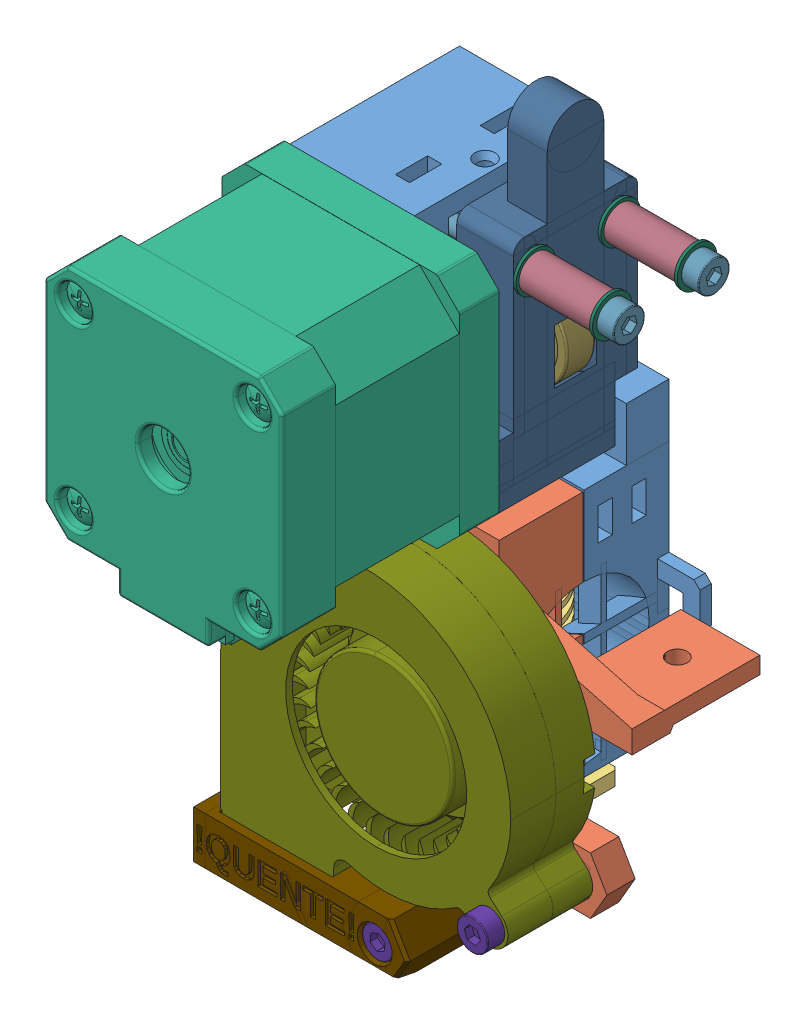
SolidWorks assembly Assembly Extruder, configuration Valor predeterminado. Lengths in mm.
Overall size (71.84 121.62 68.91).
43 component instances, 21 part files, 97 mates.
Components (placement in the parent):
- extruder-body-2: extruder-body [Valor predeterminado] at (45 44 0) x (-1 0 0) z (0 0 1) size (52.5 86 30)
- Nut DIN 934 - M3-1: Nut DIN 934 - M3 [Valor predeterminado] at (15.5 37.5 12.2) x (0 0 1) z (0.866025 0.5 0) size (2.4 5.5 6.35)
- Nut DIN 934 - M3-2: Nut DIN 934 - M3 [Valor predeterminado] at (4.5 39.5 4.79) x (0 0 1) z (-0.258819 0.965926 0) size (2.4 5.5 6.35)
- Nut DIN 934 - M3-3: Nut DIN 934 - M3 [Valor predeterminado] at (39.5 37.5 11.3) x (0 0 1) z (0.5 0.866025 0) size (2.4 5.5 6.35)
- Nut DIN 934 - M3-4: Nut DIN 934 - M3 [Valor predeterminado] at (39.5 37.5 5.2) x (0 0 1) z (1 0 0) size (2.4 5.5 6.35)
- Nut DIN 934 - M3-5: Nut DIN 934 - M3 [Valor predeterminado] at (23.3 80.7 22.5) x (1 0 0) z (0 -0.5 -0.866025) size (2.4 5.5 6.35)
- Nut DIN 934 - M3-6: Nut DIN 934 - M3 [Valor predeterminado] at (23.3 80.7 7.5) x (1 0 0) z (0 -0.5 -0.866025) size (2.4 5.5 6.35)
- Hotend E3D V6-1: Hotend E3D V6 [Valor predeterminado] at (-22.5 1.0005 15) x (0 0 -1) z (0 1 0) size (26.65 22.3 62.82)
- Nut DIN 934 - M3-7: Nut DIN 934 - M3 [Valor predeterminado] at (58.25 -1 26.81) x (0 0 -1) z (1 0 0) size (2.4 5.5 6.35)
- Nut DIN 934 - M3-8: Nut DIN 934 - M3 [Valor predeterminado] at (15.5 37.5 26.81) x (0 0 1) z (-0.866025 -0.5 0) size (2.4 5.5 6.35)
- Screw DIN 912 - M3 x 16 --- 16N-1: Screw DIN 912 - M3 x 16 --- 16N [Valor predeterminado] at (39.5 37.5 29) x (0 0 1) z (-0.911999 0.410192 0) size (19 5.5 5.5)
- Screw DIN 912 - M3 x 25 --- 18N-1: Screw DIN 912 - M3 x 25 --- 18N [Valor predeterminado] at (4.5 39.5 30) x (0 0 1) z (-0.994804 0.10181 0) size (28 5.5 5.5)
- Stepper motor Nema 17-1: Stepper motor Nema 17 [Valor predeterminado] at (-0.1278 69.2544 42.5) x (0 0 1) z (0 -1 0) size (62.01 42.01 48.01)
- PTFE tube-1: PTFE tube [Valor predeterminado] at (27.5 60.9828 15) x (0.286766 0 -0.958001) z (0 -1 0) size (4.2 4.2 49.4)
- Filament drive gear MK8 - 9 x 11-1: Filament drive gear MK8 - 9 x 11 [Valor predeterminado] at (24 65 22.65) x (0.970505 -0.241083 0) z (0.241083 0.970505 0) size (9 11 9.5)
- Screw DIN 912 - M3 x 30 --- 18N-1: Screw DIN 912 - M3 x 30 --- 18N [Valor predeterminado] at (8.5 49.5 0.5) x (0 0 -1) z (0.942704 0.333631 0) size (33 5.5 5.5)
- Screw DIN 912 - M3 x 30 --- 18N-2: Screw DIN 912 - M3 x 30 --- 18N [Valor predeterminado] at (39.5 49.5 0.5) x (0 0 -1) z (-0.421121 0.907005 0) size (33 5.5 5.5)
- extruder-idler-1: extruder-idler [Valor predeterminado] at (43.5 45.5 15) x (0 0 1) z (-1 0 0) size (25.5 57 10)
- idler-shaft-1: idler-shaft [Valor predeterminado] at (36.5 65.5 23) x (-0.827991 -0.560742 0) z (0 0 -1) size (5 5 16)
- Radial ball bearing DIN 625 - 625-1: Radial ball bearing DIN 625 - 625 [Valor predeterminado] at (36.5 65.5 15) x (0 0 1) z (-1 0 0) size (5 16 16)
- Extruder spring-1: Extruder spring [Valor predeterminado] at (44 80.7 22.5) x (0 0 -1) z (1 0 0) size (6 6 13)
- Screw DIN 912 - M3 x 40 --- 18N-1: Screw DIN 912 - M3 x 40 --- 18N [Valor predeterminado] at (60.5 80.7 22.5) x (1 0 0) z (0 0.973566 0.228405) size (43 5.5 5.5)
- Washer DIN 125A - M3-1: Washer DIN 125A - M3 [Valor predeterminado] at (57 80.7 22.5) size (0.5 7 7)
- Washer DIN 125A - M3-2: Washer DIN 125A - M3 [Valor predeterminado] at (43.5 80.7 22.5) size (0.5 7 7)
- Extruder spring-2: Extruder spring [Valor predeterminado] at (44 80.7 7.5) x (0 -0.311049 -0.950394) z (1 0 0) size (6 6 13)
- Washer DIN 125A - M3-3: Washer DIN 125A - M3 [Valor predeterminado] at (43.5 80.7 7.5) size (0.5 7 7)
- Washer DIN 125A - M3-4: Washer DIN 125A - M3 [Valor predeterminado] at (57 80.7 7.5) size (0.5 7 7)
- Screw DIN 912 - M3 x 40 --- 18N-2: Screw DIN 912 - M3 x 40 --- 18N [Valor predeterminado] at (60.5 80.7 7.5) x (1 0 0) z (0 0.973566 0.228405) size (43 5.5 5.5)
- Radial flow fan - 50 x 15-1: Radial flow fan - 50 x 15 [Valor predeterminado] at (38.25 17 30) x (1 0 0) z (0 -1 0) size (51.3 15 51.07)
- Screw DIN 912 - M3 x 20 --- 20N-1: Screw DIN 912 - M3 x 20 --- 20N [Valor predeterminado] at (58.25 -1 48) x (0 0 1) z (0.388777 -0.921332 0) size (23 5.5 5.5)
- Screw DIN 912 - M3 x 20 --- 20N-2: Screw DIN 912 - M3 x 20 --- 20N [Valor predeterminado] at (15.5 37.5 48) x (0 0 1) z (-0.788848 -0.614588 0) size (23 5.5 5.5)
- Screw DIN 912 - M3 x 20 --- 20N-3: Screw DIN 912 - M3 x 20 --- 20N [Valor predeterminado] at (40 -12 46.5) x (0 0 1) z (-0.111158 -0.993803 0) size (23 5.5 5.5)
- fan-nozzle-1: fan-nozzle [Valor predeterminado] at (10 -17 30) size (38.8 10.05 23)
- Axil flow fan - 30 x 30 x 10-1: Axil flow fan - 30 x 30 x 10 [Valor predeterminado] at (-0.34 16 15) x (0 0 -1) z (1 0 0) size (30 30 10.44)
- Screw DIN 912 - M3 x 16 --- 16N-2: Screw DIN 912 - M3 x 16 --- 16N [Valor predeterminado] at (-3.34 28 3) x (-1 0 0) z (0 -0.998394 0.056645) size (19 5.5 5.5)
- Screw DIN 912 - M3 x 16 --- 16N-3: Screw DIN 912 - M3 x 16 --- 16N [Valor predeterminado] at (-3.34 28 27) x (-1 0 0) z (0 0.857394 -0.514661) size (19 5.5 5.5)
- Screw DIN 912 - M3 x 16 --- 16N-4: Screw DIN 912 - M3 x 16 --- 16N [Valor predeterminado] at (-3.34 4 3) x (-1 0 0) z (0 -0.998394 0.056645) size (19 5.5 5.5)
- Screw DIN 912 - M3 x 16 --- 16N-5: Screw DIN 912 - M3 x 16 --- 16N [Valor predeterminado] at (-3.34 4 27) x (-1 0 0) z (0 -0.998394 0.056645) size (19 5.5 5.5)
- Washer DIN 125A - M3-5: Washer DIN 125A - M3 [Valor predeterminado] at (39.5 49.5 8) x (0 0 -1) z (0.997029 0.077029 0) size (0.5 7 7)
- Washer DIN 125A - M3-6: Washer DIN 125A - M3 [Valor predeterminado] at (39.5 49.5 30) x (0 0 -1) z (-0.467035 0.884239 0) size (0.5 7 7)
- extruder-cover-1: extruder-cover [Valor predeterminado] at (45 44 0) x (-1 0 0) z (0 0 1) size (68.5 60.8 22.6)
- Washer DIN 125A - M5-1: Washer DIN 125A - M5 [Valor predeterminado] at (36.5 65.5 12.25) x (0 0 -1) z (0.971355 -0.237634 0) size (1 10 10)
- Washer DIN 125A - M5-2: Washer DIN 125A - M5 [Valor predeterminado] at (36.5 65.5 18.75) x (0 0 -1) z (0.971355 -0.237634 0) size (1 10 10)
Mates (geometry in assembly coordinates):
- Coincidente1: coincident: plane of ? through (45 44 0) normal (0 0 -1); plane of assembly through (0 0 0) normal (0 0 1)
- Coincidente2: coincident: plane of ? through (0 44 0) normal (-1 0 0); plane of assembly through (0 0 0) normal (1 0 0)
- Coincidente3: coincident: plane of ? through (45 0 0) normal (0 -1 0); plane of assembly through (0 0 0) normal (0 1 0)
- Concêntrico1: concentric: cylinder of ? through (15.5 37.5 -0.01) axis (0 0 1) radius 1.65; cylinder of Nut DIN 934 - M3-1 through (15.5 37.5 13.4) axis (0 0 -1) radius 1.25
- Paralelo1: parallel: plane of ? through (18.2713 39.1 11) normal (-0.5 -0.866025 0); plane of Nut DIN 934 - M3-1 through (12.75 35.9123 13.4) normal (-0.5 -0.866025 0)
- Coincidente5: coincident: plane of ? through (15.5 37.5 11) normal (0 0 1); plane of Nut DIN 934 - M3-1 through (12.75 39.0877 11) normal (0 0 -1)
- Concêntrico2: concentric: cylinder of ? through (4.5 39.5 6.2) axis (0 0 1) radius 1.7; cylinder of Nut DIN 934 - M3-2 through (4.5 39.5 5.99) axis (0 0 -1) radius 1.25
- Paralelo2: parallel: plane of ? through (6.7627 41.7627 -0.01) normal (-0.258819 -0.965926 0); plane of Nut DIN 934 - M3-2 through (2.2546 37.2546 5.99) normal (-0.258819 -0.965926 0)
- Coincidente7: coincident: plane of ? through (4.5 39.5 5.99) normal (0 0 -1); plane of Nut DIN 934 - M3-2 through (2.2546 37.2546 5.99) normal (0 0 1)
- Concêntrico3: concentric: cylinder of ? through (39.5 37.5 12.7) axis (0 0 1) radius 1.65; cylinder of Nut DIN 934 - M3-3 through (39.5 37.5 12.5) axis (0 0 -1) radius 1.25
- Paralelo3: parallel: plane of ? through (46 34.65 10) normal (0 1 0); plane of Nut DIN 934 - M3-3 through (41.0877 40.25 12.5) normal (0 1 0)
- Coincidente9: coincident: plane of ? through (46 40.35 12.5) normal (0 0 -1); plane of Nut DIN 934 - M3-3 through (36.3246 37.5 12.5) normal (0 0 1)
- Concêntrico4: concentric: cylinder of ? through (39.5 37.5 -0.01) axis (0 0 1) radius 1.65; cylinder of Nut DIN 934 - M3-4 through (39.5 37.5 6.4) axis (0 0 -1) radius 1.25
- Paralelo4: parallel: plane of ? through (46 34.65 4) normal (0 1 0); plane of Nut DIN 934 - M3-4 through (37.9123 34.75 6.4) normal (0 -1 0)
- Coincidente11: coincident: plane of ? through (46 40.35 4) normal (0 0 1); plane of Nut DIN 934 - M3-4 through (37.9123 40.25 4) normal (0 0 -1)
- Coincidente12: coincident: line of ? through (30.275 80.7 22.5) axis (-1 0 0); line of Nut DIN 934 - M3-5 through (24.5 80.7 22.5) axis (-1 0 0)
- Paralelo5: parallel: plane of ? through (22 97.5 19.65) normal (0 0 1); plane of Nut DIN 934 - M3-5 through (24.5 82.2877 25.25) normal (0 0 1)
- Coincidente14: coincident: plane of ? through (24.5 97.5 19.65) normal (-1 0 0); plane of Nut DIN 934 - M3-5 through (24.5 83.8754 22.5) normal (1 0 0)
- Coincidente15: coincident: line of ? through (30.275 80.7 7.5) axis (-1 0 0); line of Nut DIN 934 - M3-6 through (24.5 80.7 7.5) axis (-1 0 0)
- Paralelo6: parallel: plane of ? through (22 97.5 4.65) normal (0 0 1); plane of Nut DIN 934 - M3-6 through (24.5 82.2877 10.25) normal (0 0 1)
- Coincidente17: coincident: plane of ? through (24.5 97.5 4.65) normal (-1 0 0); plane of Nut DIN 934 - M3-6 through (24.5 83.8754 7.5) normal (1 0 0)
- Concêntrico5: concentric: cylinder of ? through (27.5 44 15) axis (0 -1 0) radius 7.13; cylinder of Hotend E3D V6-1 through (27.5 37.0005 15) axis (0 -1 0) radius 6
- Paralelo7: parallel: plane of ? through (45 44 0) normal (1 0 0); plane of Hotend E3D V6-1 through (35.5 -8.3673 9.5) normal (1 0 0)
- Coincidente20: coincident: plane of ? through (45 37.0005 0) normal (0 -1 0); plane of Hotend E3D V6-1 through (-22.5 37.0005 15) normal (0 -1 0)
- Coincidente28: coincident: plane of ? through (3 86 30) normal (0 0 1); plane of Stepper motor Nema 17-1 through (24 65 30) normal (0 0 -1)
- Concêntrico13: concentric: cylinder of ? through (8.5 80.5 4) axis (0 0 1) radius 1.65; cylinder of Stepper motor Nema 17-1 through (8.5 80.5 33.5) axis (0 0 -1) radius 1.5
- Concêntrico14: concentric: cylinder of ? through (8.5 49.5 4) axis (0 0 1) radius 1.65; cylinder of Stepper motor Nema 17-1 through (8.5 49.5 33.5) axis (0 0 -1) radius 1.5
- Concêntrico15: concentric: cylinder of assembly; cylinder of assembly; cylinder of Hotend E3D V6-1 through (27.5 13.7005 15) axis (0 -1 0) radius 2.1; cylinder of PTFE tube-1 through (27.5 11.5827 15) axis (0 1 0) radius 2.1
- Coincidente29: coincident: plane of assembly; plane of assembly; plane of Hotend E3D V6-1 through (27.5 11.5827 15) normal (0 1 0); plane of PTFE tube-1 through (27.5 11.5827 15) normal (0 -1 0)
- Concêntrico16: concentric: cylinder of assembly; cylinder of assembly; cylinder of Stepper motor Nema 17-1 through (24 65 34.4) axis (0 0 1) radius 2.5; cylinder of Filament drive gear MK8 - 9 x 11-1 through (24 65 12.15) axis (0 0 -1) radius 2.5
- Coincidente30: coincident: line of assembly; plane of assembly; line of PTFE tube-1 through (27.5 11.5827 15) axis (0 1 0); plane of Filament drive gear MK8 - 9 x 11-1 through (24 65 15) normal (0 0 -1)
- Concêntrico17: concentric: cylinder of ? through (8.5 49.5 -1) axis (0 0 1) radius 3.1; cylinder of Screw DIN 912 - M3 x 30 --- 18N-1 through (8.5 49.5 0.5) axis (0 0 -1) radius 1.5
- Concêntrico18: concentric: cylinder of ? through (39.5 49.5 -1) axis (0 0 1) radius 3.1; cylinder of Screw DIN 912 - M3 x 30 --- 18N-2 through (39.5 49.5 0.5) axis (0 0 -1) radius 1.5
- Coincidente31: coincident: plane of ? through (39.5 49.5 3.5) normal (0 0 -1); plane of Screw DIN 912 - M3 x 30 --- 18N-2 through (37.0057 48.3419 3.5) normal (0 0 1)
- Coincidente32: coincident: plane of ? through (8.5 49.5 3.5) normal (0 0 -1); plane of Screw DIN 912 - M3 x 30 --- 18N-1 through (7.5825 52.0924 3.5) normal (0 0 1)
- Concêntrico19: concentric: cylinder of assembly; cylinder of assembly; cylinder of extruder-idler-1 through (36.5 65.5 6.5) axis (0 0 1) radius 2.5; cylinder of idler-shaft-1 through (36.5 65.5 22) axis (0 0 -1) radius 2.5
- Coincidente33: coincident: plane of assembly; plane of assembly; plane of extruder-idler-1 through (43.5 45.5 15) normal (0 0 -1); plane of idler-shaft-1 through (36.5 65.5 15) normal (0 0 -1)
- Concêntrico20: concentric: cylinder of assembly; cylinder of assembly; cylinder of Screw DIN 912 - M3 x 30 --- 18N-2 through (39.5 49.5 0.5) axis (0 0 -1) radius 1.5; cylinder of extruder-idler-1 through (39.5 49.5 0) axis (0 0 1) radius 1.7
- Coincidente34: coincident: plane of assembly through (0 0 18.75) normal (0 0 1); plane of extruder-idler-1 through (43.5 45.5 18.75) normal (0 0 1); plane of assembly
- Concêntrico21: concentric: cylinder of assembly; cylinder of assembly; cylinder of idler-shaft-1 through (36.5 65.5 22) axis (0 0 -1) radius 2.5; cylinder of Radial ball bearing DIN 625 - 625-1 through (36.5 65.5 -5.6375) axis (0 0 1) radius 2.5
- Coincidente35: coincident: plane of assembly; plane of assembly; plane of idler-shaft-1 through (36.5 65.5 15) normal (0 0 -1); plane of Radial ball bearing DIN 625 - 625-1 through (36.5 65.5 15) normal (0 0 1)
- Concêntrico22: concentric: cylinder of assembly; cylinder of assembly; cylinder of Screw DIN 912 - M3 x 40 --- 18N-1 through (60.5 80.7 22.5) axis (1 0 0) radius 1.5; cylinder of Washer DIN 125A - M3-1 through (57.5 80.7 22.5) axis (-1 0 0) radius 1.6
- Concêntrico23: concentric: cylinder of assembly; cylinder of assembly; cylinder of Screw DIN 912 - M3 x 40 --- 18N-1 through (60.5 80.7 22.5) axis (1 0 0) radius 1.5; cylinder of Washer DIN 125A - M3-2 through (44 80.7 22.5) axis (-1 0 0) radius 1.6
- Coincidente37: coincident: plane of assembly; plane of assembly; plane of Screw DIN 912 - M3 x 40 --- 18N-1 through (57.5 81.3281 19.8227) normal (-1 0 0); plane of Washer DIN 125A - M3-1 through (57.5 80.7 22.5) normal (1 0 0)
- Concêntrico24: concentric: cylinder of assembly; cylinder of assembly; cylinder of Extruder spring-1 through (57 80.7 22.5) axis (-1 0 0) radius 2.1; cylinder of Screw DIN 912 - M3 x 40 --- 18N-1 through (60.5 80.7 22.5) axis (1 0 0) radius 1.5
- Coincidente38: coincident: plane of assembly; plane of assembly; plane of Extruder spring-1 through (57 80.7 22.5) normal (1 0 0); plane of Washer DIN 125A - M3-1 through (57 80.7 22.5) normal (-1 0 0)
- Coincidente39: coincident: plane of assembly; plane of assembly; plane of Extruder spring-1 through (44 80.7 22.5) normal (-1 0 0); plane of Washer DIN 125A - M3-2 through (44 80.7 22.5) normal (1 0 0)
- Concêntrico25: concentric: cylinder of assembly; cylinder of assembly; cylinder of Nut DIN 934 - M3-5 through (24.5 80.7 22.5) axis (-1 0 0) radius 1.25; cylinder of Screw DIN 912 - M3 x 40 --- 18N-1 through (60.5 80.7 22.5) axis (1 0 0) radius 1.5
- Coincidente40: coincident: plane of assembly; plane of assembly; plane of extruder-idler-1 through (43.5 56.5 4) normal (1 0 0); plane of Washer DIN 125A - M3-2 through (43.5 80.7 22.5) normal (-1 0 0)
- Concêntrico26: concentric: cylinder of assembly; cylinder of assembly; cylinder of Washer DIN 125A - M3-4 through (57.5 80.7 7.5) axis (-1 0 0) radius 1.6; cylinder of Screw DIN 912 - M3 x 40 --- 18N-2 through (60.5 80.7 7.5) axis (1 0 0) radius 1.5
- Concêntrico27: concentric: cylinder of assembly; cylinder of assembly; cylinder of Washer DIN 125A - M3-3 through (44 80.7 7.5) axis (-1 0 0) radius 1.6; cylinder of Screw DIN 912 - M3 x 40 --- 18N-2 through (60.5 80.7 7.5) axis (1 0 0) radius 1.5
- Concêntrico28: concentric: cylinder of assembly; cylinder of assembly; cylinder of Extruder spring-2 through (57 80.7 7.5) axis (-1 0 0) radius 2.1; cylinder of Screw DIN 912 - M3 x 40 --- 18N-2 through (60.5 80.7 7.5) axis (1 0 0) radius 1.5
- Coincidente41: coincident: plane of assembly; plane of assembly; plane of Extruder spring-2 through (57 80.7 7.5) normal (1 0 0); plane of Washer DIN 125A - M3-4 through (57 80.7 7.5) normal (-1 0 0)
- Coincidente42: coincident: plane of assembly; plane of assembly; plane of Extruder spring-2 through (44 80.7 7.5) normal (-1 0 0); plane of Washer DIN 125A - M3-3 through (44 80.7 7.5) normal (1 0 0)
- Coincidente43: coincident: plane of assembly; plane of assembly; plane of Washer DIN 125A - M3-4 through (57.5 80.7 7.5) normal (1 0 0); plane of Screw DIN 912 - M3 x 40 --- 18N-2 through (57.5 81.3281 4.8227) normal (-1 0 0)
- Concêntrico29: concentric: cylinder of assembly; cylinder of assembly; cylinder of Nut DIN 934 - M3-6 through (24.5 80.7 7.5) axis (-1 0 0) radius 1.25; cylinder of Screw DIN 912 - M3 x 40 --- 18N-2 through (60.5 80.7 7.5) axis (1 0 0) radius 1.5
- Coincidente44: coincident: plane of assembly; plane of assembly; plane of extruder-idler-1 through (43.5 49.5 10) normal (1 0 0); plane of Washer DIN 125A - M3-3 through (43.5 80.7 7.5) normal (-1 0 0)
- Coincidente47: coincident: plane of assembly; plane of assembly; plane of Radial flow fan - 50 x 15-1 through (15.25 37 45) normal (0 0 1); plane of Screw DIN 912 - M3 x 20 --- 20N-1 through (55.7163 -2.0691 45) normal (0 0 -1)
- Coincidente48: coincident: plane of assembly; plane of assembly; plane of Radial flow fan - 50 x 15-1 through (15.25 37 45) normal (0 0 1); plane of Screw DIN 912 - M3 x 20 --- 20N-2 through (13.8099 39.6693 45) normal (0 0 -1)
- Coincidente50: coincident: plane of assembly; plane of assembly; plane of Screw DIN 912 - M3 x 20 --- 20N-3 through (37.267 -11.6943 43.5) normal (0 0 -1); plane of fan-nozzle-1 through (40 -12 43.5) normal (0 0 1)
- Concêntrico36: concentric: cylinder of ? through (9.999 28 3) axis (1 0 0) radius 1.35; cylinder of Axil flow fan - 30 x 30 x 10-1 through (-0.34 28 3) axis (1 0 0) radius 1.7
- Coincidente53: coincident: plane of ? through (45 44 0) normal (0 0 -1); plane of Axil flow fan - 30 x 30 x 10-1 through (-0.34 1 0) normal (0 0 -1)
- Coincidente54: coincident: plane of ? through (10 44 0) normal (-1 0 0); plane of Axil flow fan - 30 x 30 x 10-1 through (10 16 15) normal (1 0 0)
- Concêntrico38: concentric: cylinder of ? through (9.999 28 3) axis (1 0 0) radius 1.35; cylinder of Screw DIN 912 - M3 x 16 --- 16N-2 through (-3.34 28 3) axis (-1 0 0) radius 1.5
- Concêntrico39: concentric: cylinder of ? through (9.999 4 3) axis (1 0 0) radius 1.5; cylinder of Screw DIN 912 - M3 x 16 --- 16N-4 through (-3.34 4 3) axis (-1 0 0) radius 1.5
- Coincidente55: coincident: plane of assembly; plane of assembly; plane of Axil flow fan - 30 x 30 x 10-1 through (-0.34 16 15) normal (-1 0 0); plane of Screw DIN 912 - M3 x 16 --- 16N-4 through (-0.34 3.8442 0.2544) normal (1 0 0)
- Coincidente56: coincident: plane of assembly; plane of assembly; plane of Axil flow fan - 30 x 30 x 10-1 through (-0.34 16 15) normal (-1 0 0); plane of Screw DIN 912 - M3 x 16 --- 16N-3 through (-0.34 29.4153 29.3578) normal (1 0 0)
- Coincidente57: coincident: plane of assembly; plane of assembly; plane of Axil flow fan - 30 x 30 x 10-1 through (-0.34 16 15) normal (-1 0 0); plane of Screw DIN 912 - M3 x 16 --- 16N-2 through (-0.34 27.8442 0.2544) normal (1 0 0)
- Coincidente58: coincident: plane of assembly; plane of assembly; plane of Axil flow fan - 30 x 30 x 10-1 through (-0.34 16 15) normal (-1 0 0); plane of Screw DIN 912 - M3 x 16 --- 16N-5 through (-0.34 3.8442 24.2544) normal (1 0 0)
- Coincidente60: coincident: plane of assembly; plane of assembly; plane of extruder-idler-1 through (33.5 49.5 8) normal (0 0 -1); plane of Washer DIN 125A - M3-5 through (39.5 49.5 8) normal (0 0 1)
- Concêntrico41: concentric: cylinder of assembly; cylinder of assembly; cylinder of Screw DIN 912 - M3 x 30 --- 18N-2 through (39.5 49.5 0.5) axis (0 0 -1) radius 1.5; cylinder of Washer DIN 125A - M3-5 through (39.5 49.5 7.5) axis (0 0 1) radius 1.6
- Coincidente61: coincident: plane of assembly; plane of assembly; plane of extruder-idler-1 through (37.5 45.5 29.5) normal (0 0 1); plane of Washer DIN 125A - M3-6 through (39.5 49.5 29.5) normal (0 0 -1)
- Concêntrico42: concentric: cylinder of assembly; cylinder of assembly; cylinder of Screw DIN 912 - M3 x 30 --- 18N-2 through (39.5 49.5 0.5) axis (0 0 -1) radius 1.5; cylinder of Washer DIN 125A - M3-6 through (39.5 49.5 29.5) axis (0 0 1) radius 1.6
- Concêntrico43: concentric: cylinder of assembly; cylinder of assembly; cylinder of Screw DIN 912 - M3 x 20 --- 20N-3 through (40 -12 46.5) axis (0 0 1) radius 1.5; cylinder of fan-nozzle-1 through (40 -12 20) axis (0 0 1) radius 1.6
- Concêntrico46: concentric: cylinder of Nut DIN 934 - M3-7 through (58.25 -1 25.61) axis (0 0 1) radius 1.25; cylinder of ? through (58.25 -1 15) axis (0 0 1) radius 1.65
- Paralelo8: parallel: plane of Nut DIN 934 - M3-7 through (59.8377 1.75 25.61) normal (0.866025 0.5 0); plane of ? through (55.05 -1 15) normal (0.866025 0.5 0)
- Coincidente63: coincident: plane of Nut DIN 934 - M3-7 through (56.6623 -3.75 28.01) normal (0 0 1); plane of ? through (58.25 -1 28.01) normal (0 0 -1)
- Concêntrico47: concentric: cylinder of Nut DIN 934 - M3-8 through (15.5 37.5 28.01) axis (0 0 -1) radius 1.25; cylinder of ? through (15.5 37.5 -0.01) axis (0 0 1) radius 1.65
- Paralelo9: parallel: plane of Nut DIN 934 - M3-8 through (12.75 39.0877 28.01) normal (-1 0 0); plane of ? through (18.2713 35.9 11) normal (-1 0 0)
- Coincidente65: coincident: plane of Nut DIN 934 - M3-8 through (18.25 35.9123 28.01) normal (0 0 1); plane of ? through (15.5 37.5 28.01) normal (0 0 -1)
- Concêntrico48: concentric: cylinder of Hotend E3D V6-1 through (27.5 37.0005 15) axis (0 -1 0) radius 6; cylinder of ? through (27.5 44 15) axis (0 -1 0) radius 6.13
- Concêntrico49: concentric: cylinder of ? through (4.5 39.5 6.2) axis (0 0 1) radius 1.7; cylinder of ? through (4.5 39.5 6.2) axis (0 0 1) radius 1.7
- Concêntrico50: concentric: cylinder of Screw DIN 912 - M3 x 20 --- 20N-3 through (40 -12 46.5) axis (0 0 1) radius 1.5; cylinder of ? through (40 -12 20) axis (0 0 1) radius 1.5
- Coincidente66: coincident: plane of fan-nozzle-1 through (10 -17 30) normal (0 0 -1); plane of ? through (40 -12 30) normal (0 0 1)
- Coincidente67: coincident: plane of fan-nozzle-1 through (5 -12 23) normal (0 -1 0); plane of ? through (11 -12 23) normal (0 1 0)
- Concêntrico51: concentric: cylinder of Screw DIN 912 - M3 x 16 --- 16N-3 through (-3.34 28 27) axis (-1 0 0) radius 1.5; cylinder of ? through (9.999 28 27) axis (1 0 0) radius 1.35
- Concêntrico52: concentric: cylinder of Screw DIN 912 - M3 x 16 --- 16N-5 through (-3.34 4 27) axis (-1 0 0) radius 1.5; cylinder of ? through (9.999 4 27) axis (1 0 0) radius 1.5
- Concêntrico53: concentric: cylinder of Screw DIN 912 - M3 x 16 --- 16N-1 through (39.5 37.5 29) axis (0 0 1) radius 1.5; cylinder of ? through (39.5 37.5 26) axis (0 0 1) radius 3.1
- Concêntrico54: concentric: cylinder of Screw DIN 912 - M3 x 25 --- 18N-1 through (4.5 39.5 30) axis (0 0 1) radius 1.5; cylinder of ? through (4.5 39.5 27) axis (0 0 1) radius 3.1
- Coincidente68: coincident: plane of Screw DIN 912 - M3 x 16 --- 16N-1 through (40.628 40.008 26) normal (0 0 -1); plane of ? through (39.5 37.5 26) normal (0 0 1)
- Coincidente69: coincident: plane of Screw DIN 912 - M3 x 25 --- 18N-1 through (4.78 42.2357 27) normal (0 0 -1); plane of ? through (4.5 39.5 27) normal (0 0 1)
- Concêntrico55: concentric: cylinder of Radial flow fan - 50 x 15-1 through (58.25 -1 38) axis (0 0 -1) radius 2.25; cylinder of ? through (58.25 -1 15) axis (0 0 1) radius 1.65
- Paralelo10: parallel: plane of ? through (0 44 0) normal (-1 0 0); plane of Radial flow fan - 50 x 15-1 through (10.75 -8.4 37) normal (-1 0 0)
- Concêntrico56: concentric: cylinder of assembly; cylinder of assembly; cylinder of idler-shaft-1 through (36.5 65.5 22) axis (0 0 -1) radius 2.5; cylinder of Washer DIN 125A - M5-1 through (36.5 65.5 11.25) axis (0 0 1) radius 2.65
- Coincidente70: coincident: plane of assembly; plane of assembly; plane of extruder-idler-1 through (36.5 65.5 11.25) normal (0 0 1); plane of Washer DIN 125A - M5-1 through (36.5 65.5 11.25) normal (0 0 -1)
- Concêntrico57: concentric: cylinder of assembly; cylinder of assembly; cylinder of idler-shaft-1 through (36.5 65.5 22) axis (0 0 -1) radius 2.5; cylinder of Washer DIN 125A - M5-2 through (36.5 65.5 17.75) axis (0 0 1) radius 2.65
- Coincidente71: coincident: plane of assembly; plane of assembly; plane of extruder-idler-1 through (36.5 65.5 18.75) normal (0 0 -1); plane of Washer DIN 125A - M5-2 through (36.5 65.5 18.75) normal (0 0 1)
